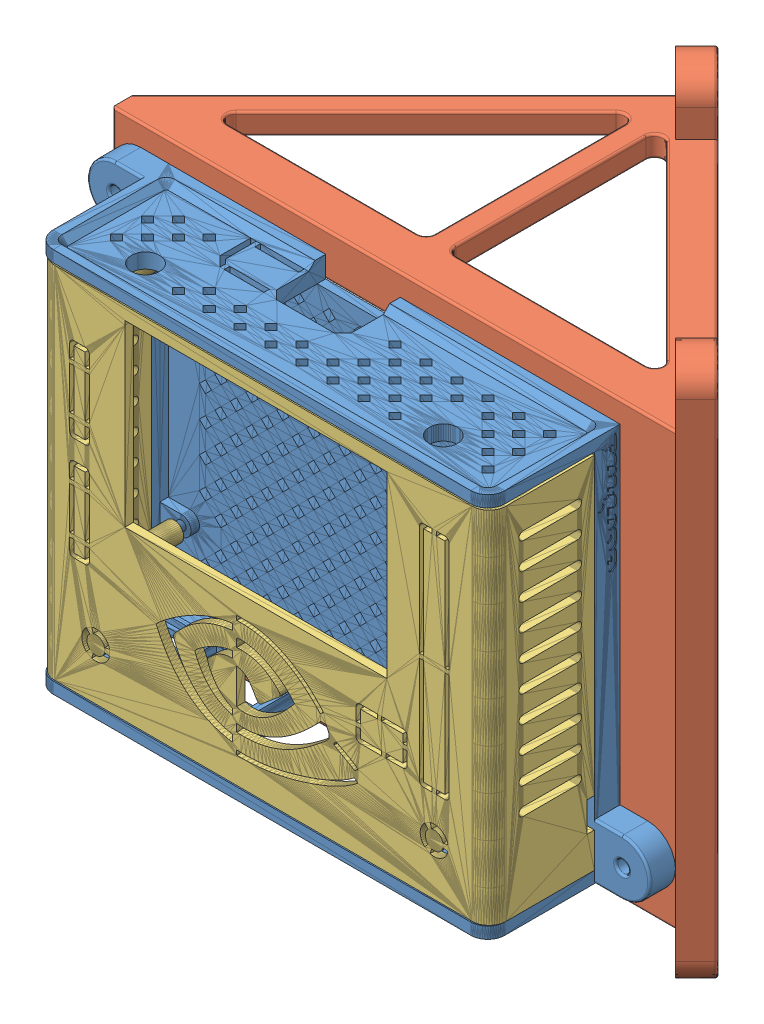
SolidWorks assembly Jetson Mount Reference Assembly, configuration Default. Lengths in mm.
Overall size (136.69 127.15 104.23).
3 component instances, 3 part files, 8 mates.
Components (placement in the parent):
- NanoBoxABSforB01_Bottom-1: NanoBoxABSforB01_Bottom [Default] at origin size (131.92 90.31 31)
- Jetson Mount-1: Jetson Mount [Default] x (-1 0 0) z (0 0 -1) size (136.69 127.15 73.23)
- NanoBoxABSforB01_Top-1: NanoBoxABSforB01_Top [Default] at (250 -0.2998 30.7) x (-1 0 0) z (0 0 -1) size (105.92 84.31 25)
Mates (geometry in assembly coordinates):
- Coincident1: coordinate: point of NanoBoxABSforB01_Bottom-1
- InPlace1: in place: plane of NanoBoxABSforB01_Bottom-1 through (0 0 0) normal (0 0 -1); plane of Jetson Mount-1 through (0 0 0) normal (0 0 -1); moOrthogonalPlaneRef_w of NanoBoxABSforB01_Bottom-1 through (0 0 0) normal (0 0 -1); plane of Jetson Mount-1 through (0 0 0) normal (0 1 0); plane of NanoBoxABSforB01_Bottom-1 through (0 0 0) normal (0 0 -1); plane of Jetson Mount-1 through (0 0 0) normal (-1 0 0); plane of NanoBoxABSforB01_Bottom-1 through (0 0 0) normal (0 0 -1); unknown of Jetson Mount-1
- Coincident2: coincident aligned: plane of NanoBoxABSforB01_Bottom-1; plane of Jetson Mount-1
- Coincident3: coincident aligned: moOrthogonalPlaneRef_w of NanoBoxABSforB01_Bottom-1 through (0 0 0) normal (0 1 0); plane of Jetson Mount-1 through (0 0 0) normal (0 1 0)
- Coincident4: coincident anti-aligned: moOrthogonalPlaneRef_w of NanoBoxABSforB01_Bottom-1 through (0 0 0) normal (1 0 0); plane of Jetson Mount-1 through (0 0 0) normal (-1 0 0)
- Coincident2: coincident anti-aligned: plane of NanoBoxABSforB01_Bottom-1 through (0 0 6) normal (0 0 1); plane of NanoBoxABSforB01_Top-1 through (250 -0.2998 6) normal (0 0 -1)
- Coincident5: coincident anti-aligned: plane of NanoBoxABSforB01_Bottom-1 through (0 62.5447 0) normal (0 1 0); plane of NanoBoxABSforB01_Top-1 through (250 62.5447 30.7) normal (0 -1 0)
- Coincident6: coincident aligned: plane of NanoBoxABSforB01_Bottom-1 through (72.0391 0 0) normal (-1 0 0); plane of NanoBoxABSforB01_Top-1 through (72.0391 -0.2998 30.7) normal (-1 0 0)
